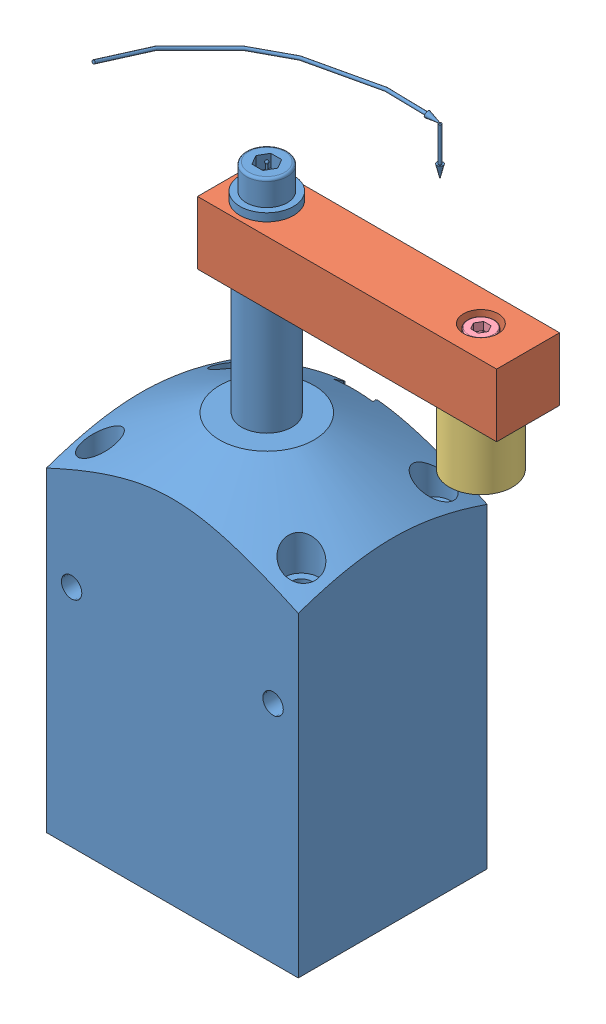
SolidWorks assembly assemb_pneu_clamp_v3, configuration Default. Lengths in mm.
Overall size (138.53 190.01 86.05).
9 component instances, 4 part files, 6 mates.
Components (placement in the parent):
- clamping_body_cw-1: clamping_body_cw [Default] at (67.3123 178.5452 175.0811) x (-1 0 0) z (0 1 0) size (95.58 86.05 190.01)
- assemb_braco_v3-1: assemb_braco_v3 [Default] at (78.3965 110.7532 94.4609) size (95 40 26.14)
  - clamping_arm_sp_v3-1: clamping_arm_sp_v3 [Default] at (-11.0842 57.292 80.6201) x (1 0 0) z (0 1 0) size (95 20 20) (hidden)
  - contact_end_full-1: contact_end_full [Default] at (56.9158 17.292 80.6201) x (-0.923645 0 -0.383249) z (0.383249 0 -0.923645) size (20 25 20) (hidden)
  - socket head cap screw_iso-2: socket head cap screw_iso [ISO 4762 M5 x 16 - 16N] at (56.9158 56.292 80.6201) x (0 -1 0) z (0 0 1) size (21 8.5 8.5) (hidden)
- assemb_braco_v3-2: assemb_braco_v3 [Default] at (147.9324 80.7532 186.1653) x (0 0 1) z (-1 0 0) size (95 40 26.14)
  - clamping_arm_sp_v3-1: clamping_arm_sp_v3 [Default] at (-11.0842 57.292 80.6201) x (1 0 0) z (0 1 0) size (95 20 20) (hidden)
  - contact_end_full-1: contact_end_full [Default] at (56.9158 17.292 80.6201) x (-0.923645 0 -0.383249) z (0.383249 0 -0.923645) size (20 25 20) (hidden)
  - socket head cap screw_iso-2: socket head cap screw_iso [ISO 4762 M5 x 16 - 16N] at (56.9158 56.292 80.6201) x (0 -1 0) z (0 0 1) size (21 8.5 8.5) (hidden)
Mates (geometry in assembly coordinates):
- Concentric1: concentric aligned: cone of clamping_body_cw-1 through (67.3123 166.0452 175.0811) axis (0 1 0); cone of assemb_braco_v3-1/clamping_arm_sp_v3-1 through (67.3123 168.0452 175.0811) axis (0 1 0)
- Parallel1: parallel aligned: plane of clamping_body_cw-1 through (107.3123 -10.9548 145.0811) normal (1 0 0); plane of assemb_braco_v3-1/clamping_arm_sp_v3-1 through (150.3123 148.0452 165.0811) normal (1 0 0)
- Coincident2: coincident aligned: circle of clamping_body_cw-1; plane of assemb_braco_v3-1/clamping_arm_sp_v3-1 through (55.3123 148.0452 185.0811) normal (0 -1 0)
- Concentric2: concentric anti-aligned: cylinder of clamping_body_cw-1 through (67.3123 108.5665 175.0811) axis (0 -1 0) radius 8; cone of assemb_braco_v3-2/clamping_arm_sp_v3-1 through (67.3123 138.0452 175.0811) axis (0 1 0)
- Parallel2: parallel aligned: plane of clamping_body_cw-1 through (107.3123 109.5452 205.0811) normal (0 0 1); plane of assemb_braco_v3-2/clamping_arm_sp_v3-1 through (77.3123 118.0452 258.0811) normal (0 0 1)
- Distance1: distance = 30 mm aligned: plane of assemb_braco_v3-2/clamping_arm_sp_v3-1 through (57.3123 138.0452 163.0811) normal (0 1 0); plane of assemb_braco_v3-1/clamping_arm_sp_v3-1 through (55.3123 168.0452 185.0811) normal (0 1 0)
